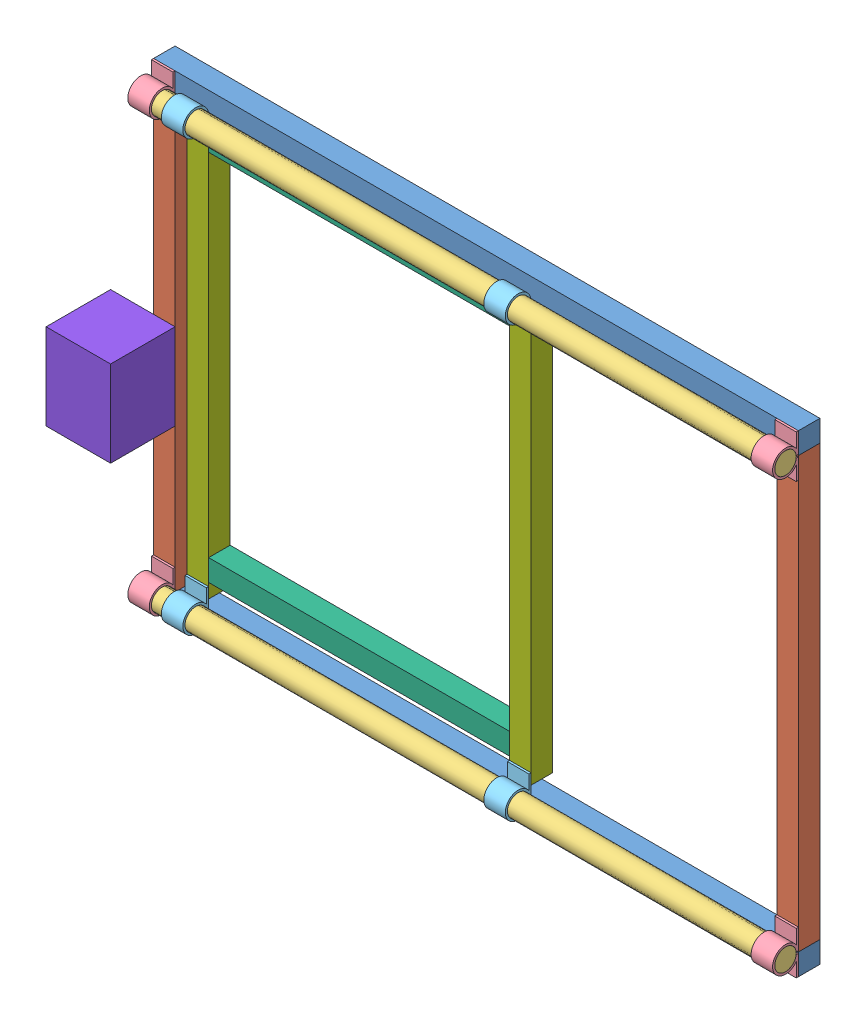
SolidWorks assembly Assem1, configuration Default. Lengths in mm.
Overall size (320 220 40).
19 component instances, 8 part files, 48 mates.
Components (placement in the parent):
- 1-1: 1 [Default] at origin size (300 10 10)
- 1-2: 1 [Default] at (0 210 0) size (300 10 10)
- 2-1: 2 [Default] at (10 10 0) x (0 1 0) z (0 0 1) size (200 10 10)
- 2-2: 2 [Default] at (290 210 0) x (0 -1 0) z (0 0 1) size (200 10 10)
- XRod-1: XRod [Default] at (0 210 6) size (300 10 10)
- XRod-2: XRod [Default] at (0 10 6) size (300 10 10)
- XRodHolder-1: XRodHolder [Default] at (0 10 6) x (1 0 0) z (0 -1 0) size (10 12 20)
- XRodHolder-2: XRodHolder [Default] at (290 10 6) x (1 0 0) z (0 -1 0) size (10 12 20)
- XRodHolder-3: XRodHolder [Default] at (0 210 6) x (1 0 0) z (0 -1 0) size (10 12 20)
- XRodHolder-4: XRodHolder [Default] at (290 210 6) x (1 0 0) z (0 -1 0) size (10 12 20)
- XRodLink-1: XRodLink [Default] at (25.6296 210 6) x (-1 0 0) z (0 1 0) size (10 12 16)
- XRodLink-2: XRodLink [Default] at (175.6296 210 6) x (-1 0 0) z (0 1 0) size (10 12 16)
- XRodLink-3: XRodLink [Default] at (15.6296 10 6) x (1 0 0) z (0 -1 0) size (10 12 16)
- XRodLink-4: XRodLink [Default] at (165.6296 10 6) x (1 0 0) z (0 -1 0) size (10 12 16)
- YBase1-1: YBase1 [Default] at (25.6296 31.6792 0) x (0 -1 0) z (0 0 1) size (10 140 10)
- YBase1-2: YBase1 [Default] at (165.6296 195 0) x (0 1 0) z (0 0 1) size (10 140 10)
- YBase2-1: YBase2 [Default] at (165.6296 15 0) size (10 190 10)
- YBase2-2: YBase2 [Default] at (15.6296 15 0) size (10 190 10)
- Motor-1: Motor [Default] at (-20 116.8844 0) x (1 0 0) z (0 0 -1) size (30 50 30)
Mates (geometry in assembly coordinates):
- Coincident1: coincident anti-aligned: plane of 1-1 through (0 10 -10) normal (0 1 0); plane of 2-1 through (0 10 0) normal (0 -1 0)
- Coincident2: coincident aligned: plane of 1-1 through (0 10 0) normal (0 0 1); plane of 2-1 through (0 10 0) normal (0 0 1)
- Coincident3: coincident aligned: plane of 1-1 through (0 10 0) normal (-1 0 0); plane of 2-1 through (0 10 -10) normal (-1 0 0)
- Coincident4: coincident anti-aligned: plane of 1-1 through (0 10 -10) normal (0 1 0); plane of 2-2 through (300 10 0) normal (0 -1 0)
- Coincident5: coincident aligned: plane of 1-1 through (300 10 0) normal (1 0 0); plane of 2-2 through (300 210 -10) normal (1 0 0)
- Coincident6: coincident aligned: plane of 1-1 through (0 10 0) normal (0 0 1); plane of 2-2 through (300 210 0) normal (0 0 1)
- Coincident7: coincident anti-aligned: plane of 1-2 through (0 210 -10) normal (0 -1 0); plane of 2-2 through (300 210 0) normal (0 1 0)
- Coincident8: coincident aligned: plane of 1-1 through (0 10 0) normal (0 0 1); plane of 1-2 through (0 220 0) normal (0 0 1)
- Coincident9: coincident aligned: plane of 1-2 through (300 220 0) normal (1 0 0); plane of 2-2 through (300 210 -10) normal (1 0 0)
- Coincident10: coincident anti-aligned: plane of 1-1 through (0 10 0) normal (0 0 1); plane of XRodHolder-1 through (10 0 0) normal (0 0 -1)
- Coincident11: coincident aligned: plane of 1-1 through (0 0 -10) normal (0 -1 0); plane of XRodHolder-1 through (10 0 1) normal (0 -1 0)
- Coincident12: coincident aligned: plane of 1-1 through (0 10 0) normal (-1 0 0); plane of XRodHolder-1 through (0 10 6) normal (-1 0 0)
- Coincident13: coincident anti-aligned: plane of 1-1 through (0 10 0) normal (0 0 1); plane of XRodHolder-2 through (300 0 0) normal (0 0 -1)
- Coincident14: coincident aligned: plane of 1-1 through (0 0 -10) normal (0 -1 0); plane of XRodHolder-2 through (300 0 1) normal (0 -1 0)
- Coincident15: coincident aligned: plane of 1-1 through (300 10 0) normal (1 0 0); plane of XRodHolder-2 through (300 10 6) normal (1 0 0)
- Coincident16: coincident anti-aligned: plane of 1-2 through (0 220 0) normal (0 0 1); plane of XRodHolder-4 through (300 200 0) normal (0 0 -1)
- Coincident17: coincident aligned: plane of 1-2 through (0 220 -10) normal (0 1 0); plane of XRodHolder-4 through (300 220 1) normal (0 1 0)
- Coincident18: coincident aligned: plane of 1-2 through (300 220 0) normal (1 0 0); plane of XRodHolder-4 through (300 210 6) normal (1 0 0)
- Coincident19: coincident anti-aligned: plane of 1-2 through (0 220 0) normal (0 0 1); plane of XRodHolder-3 through (10 200 0) normal (0 0 -1)
- Coincident20: coincident aligned: plane of 1-2 through (0 220 0) normal (-1 0 0); plane of XRodHolder-3 through (0 210 6) normal (-1 0 0)
- Coincident21: coincident aligned: plane of 1-2 through (0 220 -10) normal (0 1 0); plane of XRodHolder-3 through (10 220 1) normal (0 1 0)
- Concentric1: concentric aligned: cylinder of XRod-1 through (300 210 6) axis (-1 0 0) radius 5; cylinder of XRodHolder-3 through (10 210 6) axis (-1 0 0) radius 5
- Coincident22: coincident aligned: plane of XRod-1 through (0 210 6) normal (-1 0 0); plane of XRodHolder-3 through (0 210 6) normal (-1 0 0)
- Concentric2: concentric aligned: cylinder of XRod-2 through (300 10 6) axis (-1 0 0) radius 5; cylinder of XRodHolder-1 through (10 10 6) axis (-1 0 0) radius 5
- Coincident23: coincident aligned: plane of XRod-2 through (0 10 6) normal (-1 0 0); plane of XRodHolder-1 through (0 10 6) normal (-1 0 0)
- Concentric3: concentric anti-aligned: cylinder of XRod-1 through (300 210 6) axis (-1 0 0) radius 5; cylinder of XRodLink-1 through (15.6296 210 6) axis (1 0 0) radius 5
- Concentric4: concentric anti-aligned: cylinder of XRod-1 through (300 210 6) axis (-1 0 0) radius 5; cylinder of XRodLink-2 through (165.6296 210 6) axis (1 0 0) radius 5
- Concentric5: concentric aligned: cylinder of XRod-2 through (300 10 6) axis (-1 0 0) radius 5; cylinder of XRodLink-3 through (25.6296 10 6) axis (-1 0 0) radius 5
- Concentric6: concentric aligned: cylinder of XRod-2 through (300 10 6) axis (-1 0 0) radius 5; cylinder of XRodLink-4 through (175.6296 10 6) axis (-1 0 0) radius 5
- Coincident24: coincident anti-aligned: plane of XRodLink-2 through (165.6296 200 0) normal (0 0 -1); plane of YBase2-1 through (165.6296 205 0) normal (0 0 1)
- Coincident25: coincident anti-aligned: plane of XRodLink-4 through (175.6296 20 0) normal (0 0 -1); plane of YBase2-1 through (165.6296 205 0) normal (0 0 1)
- Coincident26: coincident aligned: plane of XRodLink-2 through (165.6296 210 6) normal (-1 0 0); plane of YBase2-1 through (165.6296 205 0) normal (-1 0 0)
- Distance1: distance = 5 mm: plane of YBase2-1 through (165.6296 205 -10) normal (0 1 0); line of XRodLink-2 through (165.6296 200 0) axis (0 0 1)
- Coincident32: coincident aligned: plane of XRodLink-4 through (165.6296 10 6) normal (-1 0 0); plane of YBase2-1 through (165.6296 205 0) normal (-1 0 0)
- Coincident33: coincident anti-aligned: plane of XRodLink-1 through (15.6296 200 0) normal (0 0 -1); plane of YBase2-2 through (15.6296 205 0) normal (0 0 1)
- Coincident34: coincident anti-aligned: plane of XRodLink-3 through (25.6296 20 0) normal (0 0 -1); plane of YBase2-2 through (15.6296 205 0) normal (0 0 1)
- Coincident35: coincident aligned: plane of XRodLink-1 through (15.6296 210 6) normal (-1 0 0); plane of YBase2-2 through (15.6296 205 0) normal (-1 0 0)
- Coincident36: coincident aligned: plane of XRodLink-3 through (15.6296 10 6) normal (-1 0 0); plane of YBase2-2 through (15.6296 205 0) normal (-1 0 0)
- Distance2: distance = 5 mm anti-aligned: plane of YBase2-2 through (15.6296 205 -10) normal (0 1 0); plane of XRodLink-1 through (15.6296 200 1) normal (0 -1 0)
- Coincident38: coincident anti-aligned: plane of YBase1-2 through (25.6296 195 -10) normal (-1 0 0); plane of YBase2-2 through (25.6296 205 0) normal (1 0 0)
- Coincident39: coincident aligned: plane of YBase1-2 through (25.6296 195 0) normal (0 0 1); plane of YBase2-2 through (15.6296 205 0) normal (0 0 1)
- Coincident40: coincident aligned: plane of YBase1-2 through (25.6296 205 0) normal (0 1 0); plane of YBase2-2 through (15.6296 205 -10) normal (0 1 0)
- Coincident41: coincident anti-aligned: plane of YBase1-2 through (165.6296 195 -10) normal (1 0 0); plane of YBase2-1 through (165.6296 205 0) normal (-1 0 0)
- Coincident42: coincident anti-aligned: plane of YBase1-1 through (25.6296 31.6792 -10) normal (-1 0 0); plane of YBase2-2 through (25.6296 205 0) normal (1 0 0)
- Coincident43: coincident aligned: plane of YBase1-1 through (165.6296 31.6792 0) normal (0 0 1); plane of YBase2-2 through (15.6296 205 0) normal (0 0 1)
- Coincident44: coincident anti-aligned: plane of YBase1-1 through (165.6296 31.6792 -10) normal (1 0 0); plane of YBase2-1 through (165.6296 205 0) normal (-1 0 0)
- Coincident45: coincident anti-aligned: plane of 2-1 through (0 10 0) normal (0 0 1); plane of Motor-1 through (-20 76.8844 0) normal (0 0 -1)
- Coincident46: coincident aligned: plane of 2-1 through (10 10 -10) normal (1 0 0); plane of Motor-1 through (10 76.8844 0) normal (1 0 0)
